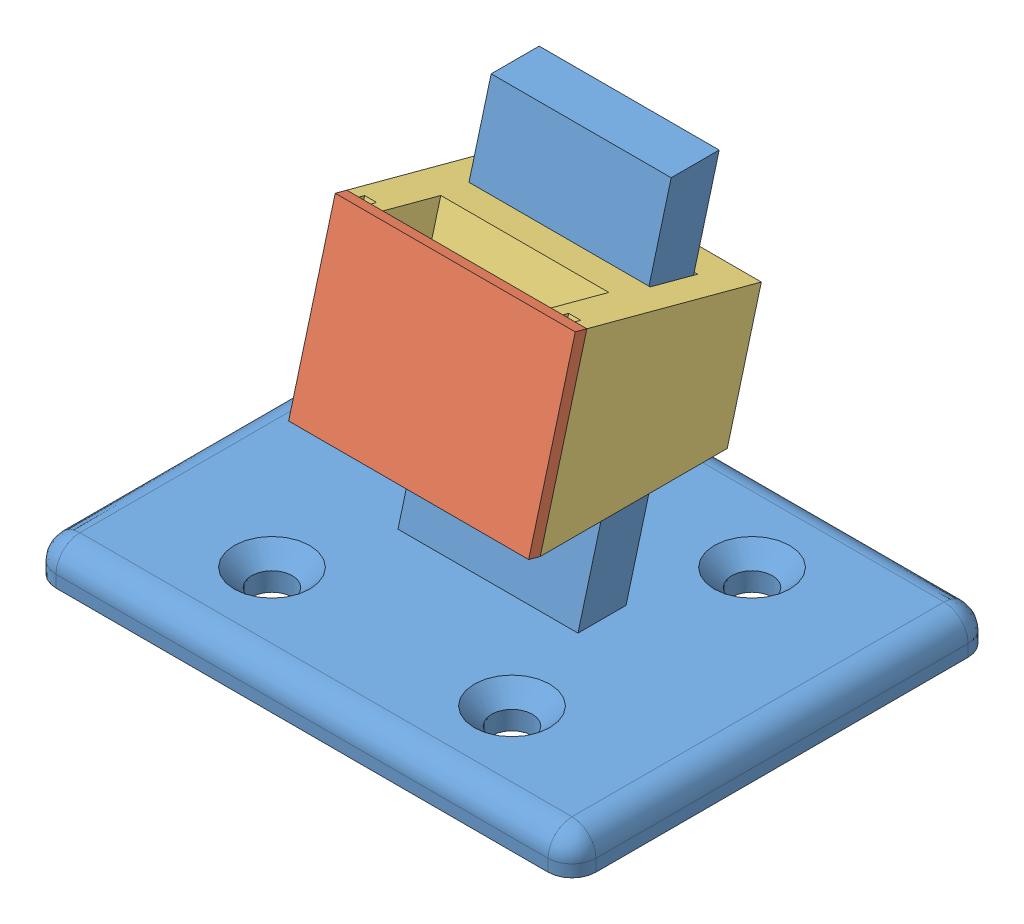
SolidWorks assembly Assembly, configuration Default. Lengths in mm.
Overall size (45 36.6 35).
3 component instances, 3 part files, 4 mates.
Components (placement in the parent):
- base-1: base [Default] at (15.0271 12.8544 42.6967) size (45 36.6 35)
- sample-1: sample [Default] at (15.0771 32.754 48.4507) x (1 0 0) z (0 0.258819 0.965926) size (20 15 1)
- top2-1: top2 [Default] at (15.0771 22.9084 40.6842) x (0 -0.258819 -0.965926) z (1 0 0) size (15.05 15 20)
Mates (geometry in assembly coordinates):
- Coincident11: coincident anti-aligned: plane of base-1 through (7.5271 44.8322 36.9321) normal (0 0.258819 0.965926); plane of top2-1 through (15.0771 23.439 42.6644) normal (0 -0.258819 -0.965926)
- Coincident12: coincident anti-aligned: plane of base-1 through (7.5271 44.8322 36.9321) normal (-1 0 0); plane of top2-1 through (7.5271 23.439 42.6644) normal (1 0 0)
- Coincident13: coincident aligned: line of sample-1 through (25.0771 25.5095 50.3918) axis (0 0.965926 -0.258819); line of top2-1 through (25.0771 25.5095 50.3918) axis (0 0.965926 -0.258819)
- Coincident14: coincident aligned: line of sample-1 through (5.0771 25.5095 50.3918) axis (1 0 0); line of top2-1 through (5.0771 25.5095 50.3918) axis (1 0 0)
